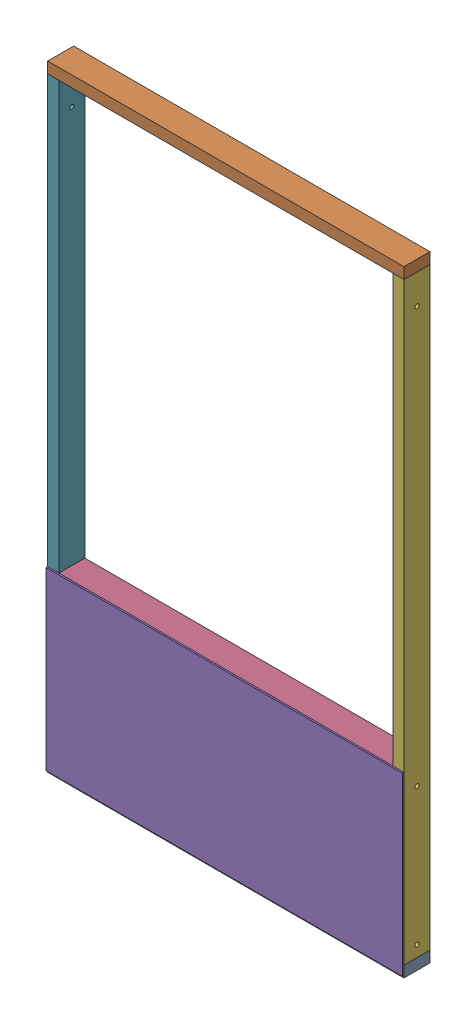
SolidWorks assembly basic panel, configuration Default. Lengths in mm.
Overall size (1219.2 2108.2 94.46).
7 component instances, 5 part files, 18 mates.
Components (placement in the parent):
- 2x4x48-1: 2x4x48 [Default] x (0 0 -1) z (0 1 0) size (88.9 1219.2 38.1)
- 2x4x48-2: 2x4x48 [Default] at (0 2070.1 0) x (0 0 1) z (0 -1 0) size (88.9 1219.2 38.1)
- 2x4x21-1: 2x4x21 [Default] at (-609.6 552.45 0) x (0 0 -1) z (-1 0 0) size (88.9 533.4 38.1)
- 2x4x45-1: 2x4x45 [Default] at (-38.1 571.5 0) x (0 0 1) z (0 -1 0) size (88.9 1143 38.1)
- plywoodx48x23.7 plywood-1: plywoodx48x23.7 plywood [Default] at (-609.6 289.56 44.45) x (1 0 0) z (0 -1 0) size (1219.2 5.56 601.98)
- 2x4x80-Hole-1: 2x4x80-Hole [Default] at (-19.05 19.05 0) x (0 0 -1) z (1 0 0) size (88.9 2032 38.1)
- 2x4x80-Hole-2: 2x4x80-Hole [Default] at (-1200.15 19.05 0) x (0 0 1) z (-1 0 0) size (88.9 2032 38.1)
Mates (geometry in assembly coordinates):
- Coincident10: coincident anti-aligned: plane of 2x4x48-1 through (-1219.2 19.05 44.45) normal (0 1 0); plane of 2x4x21-1 through (-609.6 19.05 0) normal (0 -1 0)
- Coincident11: coincident aligned: plane of 2x4x48-1 through (-1219.2 19.05 44.45) normal (0 0 1); plane of 2x4x21-1 through (-628.65 19.05 44.45) normal (0 0 1)
- Coincident12: coincident anti-aligned: plane of 2x4x21-1 through (-609.6 552.45 0) normal (0 1 0); plane of 2x4x45-1 through (-1181.1 552.45 -44.45) normal (0 -1 0)
- Coincident13: coincident aligned: plane of 2x4x21-1 through (-628.65 19.05 44.45) normal (0 0 1); plane of 2x4x45-1 through (-1181.1 552.45 44.45) normal (0 0 1)
- Coincident18: coincident anti-aligned: plane of 2x4x48-1 through (-1219.2 19.05 44.45) normal (0 1 0); plane of 2x4x80-Hole-2 through (-1200.15 19.05 0) normal (0 -1 0)
- Coincident19: coincident aligned: plane of 2x4x48-1 through (-1219.2 0 0) normal (-1 0 0); plane of 2x4x80-Hole-2 through (-1219.2 2051.05 -44.45) normal (-1 0 0)
- Coincident20: coincident aligned: plane of 2x4x48-1 through (-1219.2 19.05 -44.45) normal (0 0 -1); plane of 2x4x80-Hole-2 through (-1219.2 2051.05 -44.45) normal (0 0 -1)
- Coincident21: coincident anti-aligned: plane of 2x4x48-1 through (-1219.2 19.05 44.45) normal (0 1 0); plane of 2x4x80-Hole-1 through (-19.05 19.05 0) normal (0 -1 0)
- Coincident22: coincident aligned: plane of 2x4x48-1 through (0 0 0) normal (1 0 0); plane of 2x4x80-Hole-1 through (0 2051.05 44.45) normal (1 0 0)
- Coincident23: coincident anti-aligned: plane of plywoodx48x23.7 plywood-1 through (-609.6 289.56 44.45) normal (0 0 -1); plane of 2x4x80-Hole-1 through (0 2051.05 44.45) normal (0 0 1)
- Coincident24: coincident aligned: plane of 2x4x48-1 through (-1219.2 19.05 -44.45) normal (0 0 -1); plane of 2x4x80-Hole-1 through (0 2051.05 -44.45) normal (0 0 -1)
- Coincident25: coincident aligned: plane of plywoodx48x23.7 plywood-1 through (0 -11.43 50.0063) normal (1 0 0); plane of 2x4x80-Hole-1 through (0 2051.05 44.45) normal (1 0 0)
- Coincident26: coincident anti-aligned: plane of 2x4x45-1 through (-38.1 571.5 0) normal (1 0 0); plane of 2x4x80-Hole-1 through (-38.1 2051.05 44.45) normal (-1 0 0)
- Symmetric1: symmetric aligned: plane of 2x4x48-1 through (0 0 0) normal (1 0 0); plane of 2x4x21-1 through (-1219.2 0 0) normal (-1 0 0); plane of 2x4x48-1 through (-609.6 552.45 0) normal (-1 0 0)
- Coincident27: coincident anti-aligned: plane of 2x4x48-2 through (-1219.2 2051.05 -44.45) normal (0 -1 0); plane of 2x4x80-Hole-2 through (-1200.15 2051.05 0) normal (0 1 0)
- Coincident28: coincident aligned: plane of 2x4x48-2 through (-1219.2 2051.05 -44.45) normal (0 0 -1); plane of 2x4x80-Hole-2 through (-1219.2 2051.05 -44.45) normal (0 0 -1)
- Coincident29: coincident aligned: plane of 2x4x48-2 through (-1219.2 2070.1 0) normal (-1 0 0); plane of 2x4x80-Hole-2 through (-1219.2 2051.05 -44.45) normal (-1 0 0)
- Distance1: distance = 7.62 mm aligned: plane of plywoodx48x23.7 plywood-1 through (-1219.2 -11.43 50.0063) normal (0 -1 0); plane of 2x4x48-1 through (-1219.2 -19.05 44.45) normal (0 -1 0)
